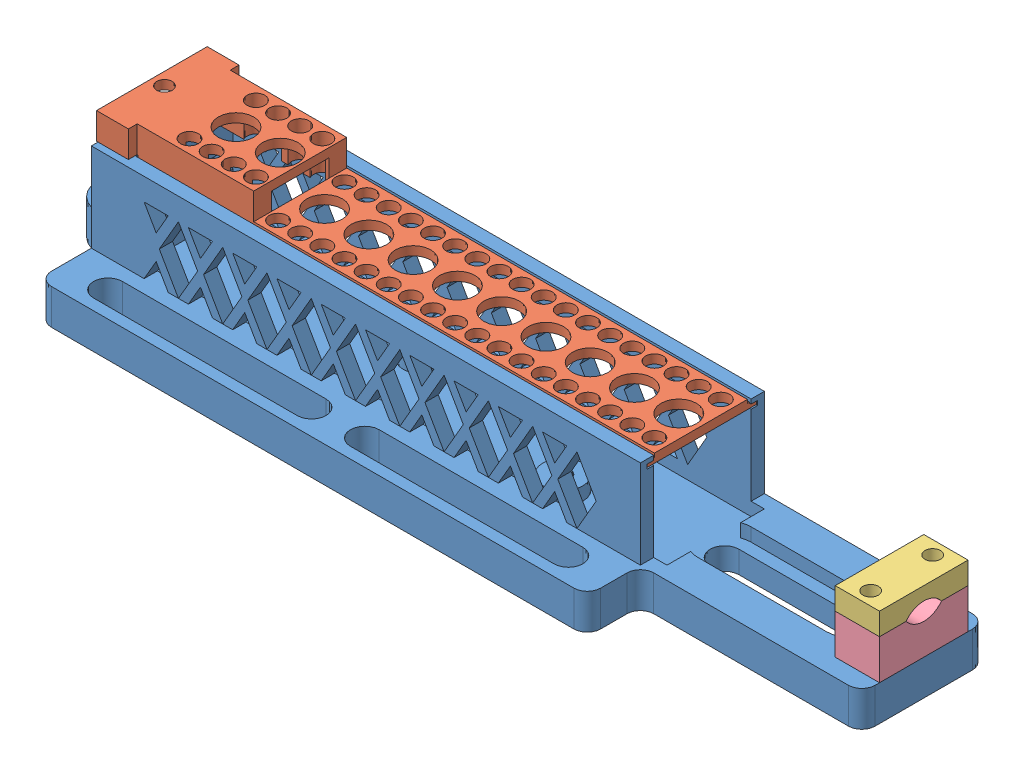
SolidWorks assembly hum_housing, configuration Standard. Lengths in mm.
Overall size (186.5 34 40).
4 component instances, 4 part files, 8 mates.
Components (placement in the parent):
- hum_base-1: hum_base [Standard] at (-3.0653 -6.5639 0) size (186.5 28 40)
- hum_lid-1: hum_lid [Standard] at (58.597 52.8057 22.1559) x (-1 0 0) z (0 0 -1) size (124 8 25)
- hum_cable-clamp2-2: hum_cable-clamp2 [Standard] at (98.9347 15.4361 -16) x (0 0 1) z (1 0 0) size (20 5 10)
- hum_cable-clamp1-3: hum_cable-clamp1 [Standard] at (98.9347 1.4361 4) x (0 0 -1) z (1 0 0) size (20 9 10)
Mates (geometry in assembly coordinates):
- Parallel1: parallel anti-aligned: line of hum_base-1 through (58.9347 20.4361 5) axis (-1 0 0); line of hum_lid-1 through (-58.203 27.4361 4.5) axis (1 0 0)
- Deckungsgleich4: coincident anti-aligned: line of hum_base-1 through (108.9347 1.4361 -17) axis (0 0 1); line of hum_cable-clamp1-3 through (108.9347 1.4361 4) axis (0 0 -1)
- Deckungsgleich5: coincident aligned: line of hum_cable-clamp2-2 through (108.9347 15.4361 4) axis (0 -1 0); line of hum_cable-clamp1-3 through (108.9347 10.4361 4) axis (0 -1 0)
- Konzentrisch2: concentric aligned: circle of hum_base-1; circle of hum_cable-clamp1-3
- Deckungsgleich6: coincident anti-aligned: line of hum_cable-clamp2-2 through (108.9347 10.4361 -10) axis (0 0 -1); line of hum_cable-clamp1-3 through (108.9347 10.4361 -16) axis (0 0 1)
- Konzentrisch3: concentric: circle of hum_base-1; circle of hum_lid-1
- Deckungsgleich9: coincident aligned: line of hum_base-1 through (-59.0653 19.4361 6.5) axis (1 0 0); line of hum_lid-1 through (-59.403 19.4361 6.5) axis (1 0 0)
- Parallel2: parallel aligned: plane of hum_base-1 through (-3.0653 21.4361 0) normal (0 1 0); plane of hum_lid-1 through (58.597 21.4361 22.1559) normal (0 1 0)
